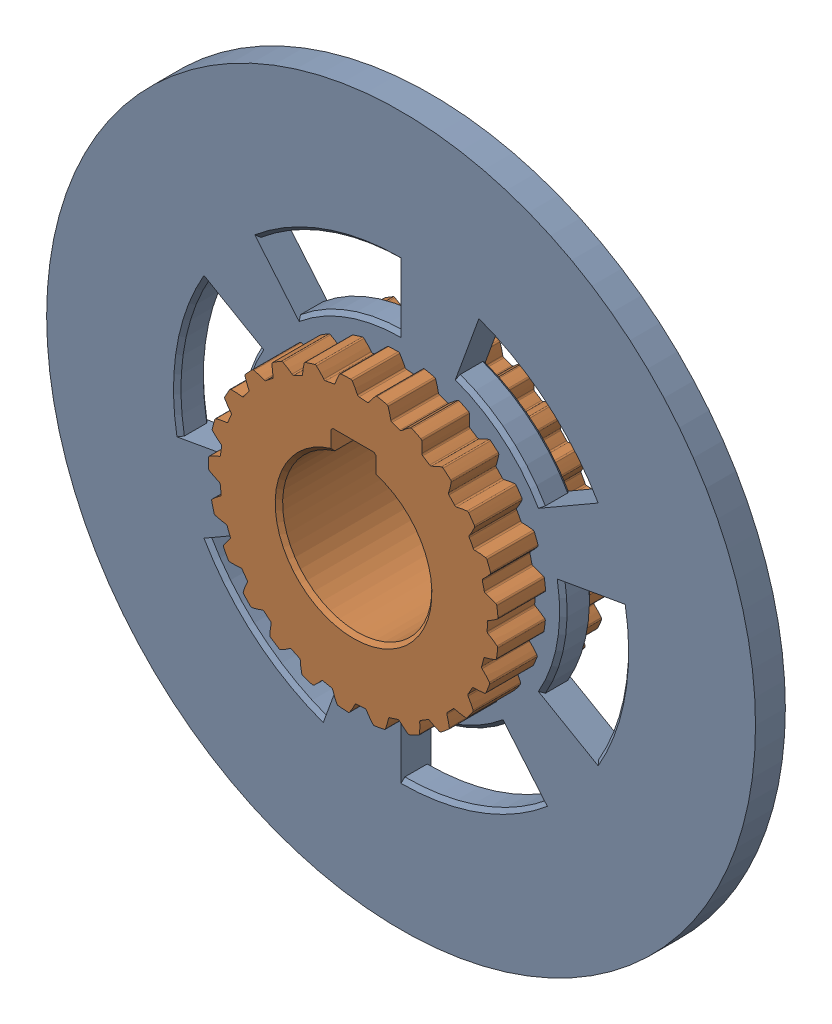
SolidWorks assembly Dog_Mechanism_4_&_5, configuration Default. Lengths in mm.
Overall size (190 190 30).
2 component instances, 2 part files, 1 mates.
Components (placement in the parent):
- Dog_Ring_4_&_5-1: Dog_Ring_4_&_5 [Default] at (-9.3225 6.0962 3.092) size (190 190 8)
- Dog_Ring_Sleeve_gear_4_5-1: Dog_Ring_Sleeve_gear_4_5 [Default] at (-9.3225 6.0962 -6.1624) size (77.57 77.67 30)
Mates (geometry in assembly coordinates):
- Concentric1: concentric aligned: cylinder of Dog_Ring_4_&_5-1 through (-9.3225 6.0962 11.092) axis (0 0 -1) radius 95; cylinder of Dog_Ring_Sleeve_gear_4_5-1 through (-9.3225 6.0962 23.8376) axis (0 0 -1) radius 38.85
